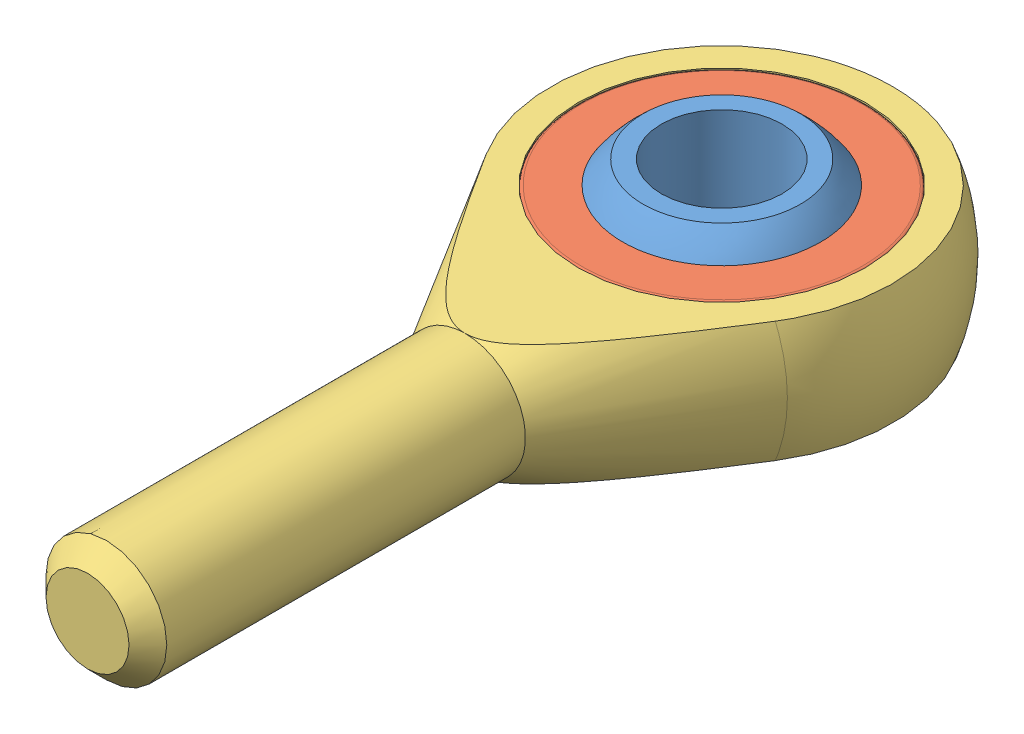
SolidWorks assembly Przegub kulowy_GN 648.2_8, configuration Domyślna. Lengths in mm.
Overall size (24 12 54).
3 component instances, 3 part files, 8 mates.
Components (placement in the parent):
- ROD-END-GN-648.2-1-8-1: ROD-END-GN-648.2-1-8 [8] x (-1 0 0) z (0 0 -1) size (15.88 12 15.88)
- ROD-END-GN-648.2-2-8-1: ROD-END-GN-648.2-2-8 [8] x (0.997964 0 0.063787) z (-0.063787 0 0.997964) size (19 9 19)
- ROD-END-GN-648.2-3-8-1: ROD-END-GN-648.2-3-8 [8] at (0 0.5 0) size (24 8 54)
Mates (geometry in assembly coordinates):
- Koncentryczne1: concentric: sphere of ROD-END-GN-648.2-2-8-1; sphere of ROD-END-GN-648.2-1-8-1
- Limit kąta1: limit planar angle = 0 rad aligned: cylinder of ROD-END-GN-648.2-1-8-1 through (0 -11.1 0) axis (0 -1 0) radius 4
- Limit kąta2: limit planar angle = 0 rad aligned: cylinder of ROD-END-GN-648.2-2-8-1 through (0 4.5 0) axis (0 -1 0) radius 9.5
- Koncentryczne5: concentric anti-aligned: cylinder of ROD-END-GN-648.2-3-8-1 through (0 -3.5 0) axis (0 1 0) radius 9.5; cylinder of ROD-END-GN-648.2-2-8-1 through (0 4.5 0) axis (0 -1 0) radius 9.5
- Wspólnie1: coincident aligned: plane of ROD-END-GN-648.2-3-8-1 through (-12 4.5 17) normal (0 1 0); plane of ROD-END-GN-648.2-2-8-1 through (0 4.5 0) normal (0 1 0)
- Wspólnie2: coincident anti-aligned: plane of ROD-END-GN-648.2-1-8-1 through (0 0 0) normal (0 0 -1)
- Wspólnie3: coincident aligned: plane of ROD-END-GN-648.2-1-8-1 through (0 0 0) normal (0 1 0)
- Wspólnie4: coincident anti-aligned: plane of ROD-END-GN-648.2-1-8-1 through (0 0 0) normal (-1 0 0)
